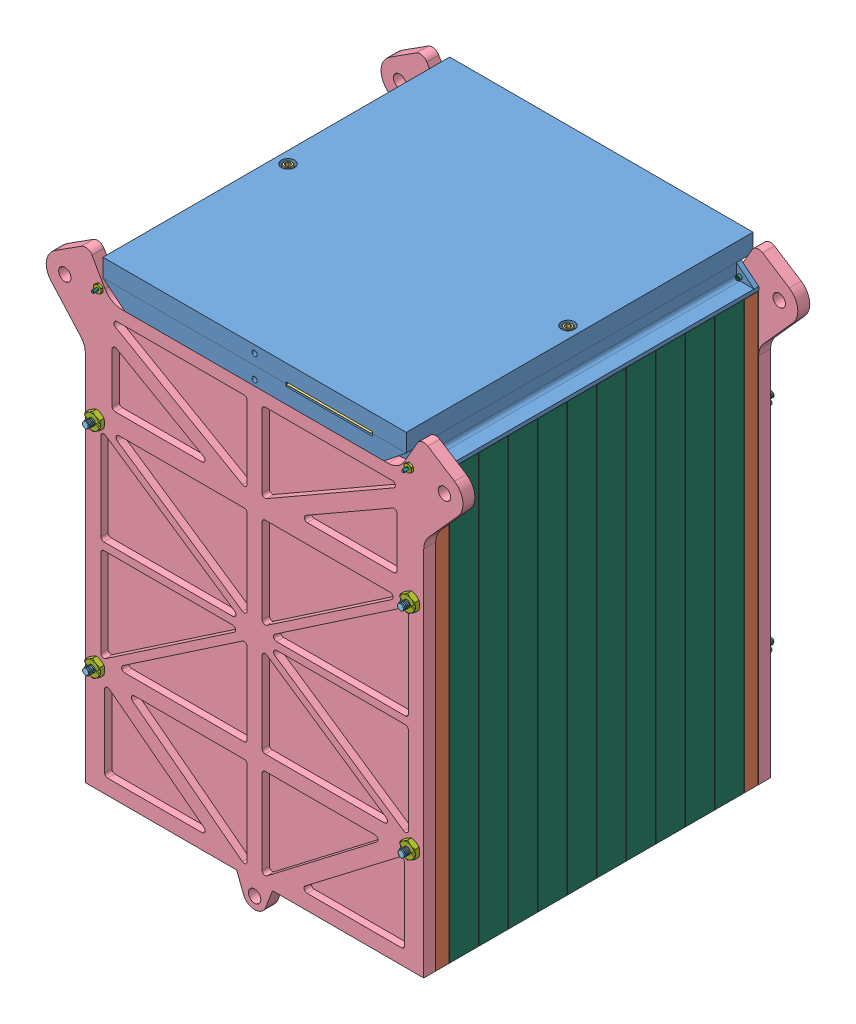
SolidWorks assembly Even Stack, configuration Default. Lengths in mm.
Overall size (221.56 260.06 197.4).
291 component instances, 25 part files, 68 mates.
Components (placement in the parent):
- Tab Cover Even-1: Tab Cover Even [Default] at (178.2277 374.9734 444.4742) x (-1 0 0) z (0 -1 0) size (180.05 184.28 19.05)
- Steel Hex 4-40 Grade 2-1: Steel Hex 4-40 Grade 2 [90480A005] at (103.8227 367.2577 444.4742) size (6.35 2.87 7.33)
- Steel Hex 4-40 Grade 2-2: Steel Hex 4-40 Grade 2 [90480A005] at (252.6327 367.2577 444.4742) size (6.35 2.87 7.33)
- Socket 4-40 0.625in-3: Socket 4-40 0.625in [91251A112] at (103.8227 365.6234 444.4742) x (0.871261 0 -0.49082) z (0 -1 0) size (4.65 4.65 19.13)
- Socket 4-40 0.625in-4: Socket 4-40 0.625in [91251A112] at (252.6327 365.6234 444.4742) x (1 0 0) z (0 -1 0) size (4.65 4.65 19.13)
- Two Cell Module-1: Two Cell Module [Default] at (101.24 129.6114 180.5218) size (179.74 245.1 23.68)
  - Cell Tab Config A-1: Cell Tab Config A [Default<As Machined>] at (76.9877 122.2307 189.17) size (160.6 237.16 14.27)
  - Cell Tab Config B-1: Cell Tab Config B [Default<As Machined>] at (76.9877 122.2307 197.4606) x (-1 0 0) z (0 0 -1) size (160.6 237.16 14.66)
  - Tab Load Spreader-1: Tab Load Spreader [Default] at (116.6877 245.8907 191.0069) x (-1 0 0) z (0 1 0) size (56.96 6.41 2.54)
  - Tab Load Spreader-2: Tab Load Spreader [Default] at (37.2877 245.8907 183.3655) x (-1 0 0) z (0 1 0) size (56.96 6.41 2.54)
  - Tab Load Spreader-3: Tab Load Spreader [Default] at (116.6877 242.8507 191.0069) x (-1 0 0) z (0 1 0) size (56.96 6.41 2.54)
  - Tab Load Spreader-4: Tab Load Spreader [Default] at (37.2877 242.8507 183.3655) x (-1 0 0) z (0 1 0) size (56.96 6.41 2.54)
  - Steel Toplock 6-32 Grade 2-1: Steel Toplock 6-32 Grade 2 [91837A008] at (141.9657 242.8507 191.0069) x (1 0 0) z (0 -1 0) size (7.94 9.17 3.14)
  - Steel 6-32 0.4375in-1: Steel 6-32 0.4375in [91251A178] at (141.9657 237.3182 191.0069) x (1 0 0) z (0 -1 0) size (5.74 5.74 15.07)
  - Steel Toplock 6-32 Grade 2-2: Steel Toplock 6-32 Grade 2 [91837A008] at (91.4097 242.8507 191.0069) x (1 0 0) z (0 -1 0) size (7.94 9.17 3.14)
  - Steel Toplock 6-32 Grade 2-3: Steel Toplock 6-32 Grade 2 [91837A008] at (62.5657 242.8507 183.3655) x (1 0 0) z (0 -1 0) size (7.94 9.17 3.14)
  - Steel Toplock 6-32 Grade 2-4: Steel Toplock 6-32 Grade 2 [91837A008] at (12.0097 242.8507 183.3655) x (1 0 0) z (0 -1 0) size (7.94 9.17 3.14)
  - Steel 6-32 0.4375in-2: Steel 6-32 0.4375in [91251A178] at (91.4097 237.3182 191.0069) x (1 0 0) z (0 -1 0) size (5.74 5.74 15.07)
  - Steel 6-32 0.4375in-3: Steel 6-32 0.4375in [91251A178] at (62.5657 237.3182 183.3655) x (1 0 0) z (0 -1 0) size (5.74 5.74 15.07)
  - Steel 6-32 0.4375in-4: Steel 6-32 0.4375in [91251A178] at (12.0097 237.3182 183.3655) x (1 0 0) z (0 -1 0) size (5.74 5.74 15.07)
  - Cell Board Middle-1: Cell Board Middle [Default] at (76.9877 244.9032 188.87) x (-1 0 0) z (0 0 1) size (20.32 17.15 2.64)
  - Cell Board Middle-2: Cell Board Middle [Default] at (76.9877 244.9032 197.1606) size (20.32 17.15 2.64)
  - Repeating Frame Outer-1: Repeating Frame Outer [Default] at (76.9877 115.9807 198.7766) size (179.3 226.63 1.59)
  - Repeating Frame Outer-2: Repeating Frame Outer [Default] at (76.9877 115.9807 186.2665) size (179.3 226.63 1.59)
  - Repeating Frame Inner-1: Repeating Frame Inner [Default] at (76.9877 116.0307 190.8106) size (179.3 226.73 6.35)
  - Insulation Film Back-1: Insulation Film Back [Default] at (76.9877 122.0246 185.62) x (-1 0 0) z (0 0 -1) size (179.74 227.29 0.36)
  - Insulation Film Full-1: Insulation Film Full [Default] at (76.9876 122.0664 201.0792) x (-1 0 0) z (0 0 -1) size (179.74 227.22 15.52)
  - Cell Load Spreader-1: Cell Load Spreader [Default] at (76.9877 115.9807 192.72) size (154 205.5 1.19)
  - Heat Sink Full-1: Heat Sink Full [Default] at (76.9877 122.0321 201.2316) x (-1 0 0) z (0 0 -1) size (179.74 227.15 15.45)
- Positive End Module-1: Positive End Module [Default] at (225.9097 129.8563 535.5842) x (-1 0 0) z (0 0 -1) size (179.74 245.1 14.97)
  - Cell Tab Config B Positive End-1: Cell Tab Config B Positive End [Default<As Machined>] at (47.682 121.9858 173.2819) size (160.6 236.86 14.97)
  - Repeating Frame Outer-1: Repeating Frame Outer [Default] at (47.682 115.7358 173.5819) size (179.3 226.63 1.59)
  - Repeating Frame Outer-2: Repeating Frame Outer [Default] at (47.682 115.7358 175.1694) size (179.3 226.63 1.59)
  - Repeating Frame Outer-3: Repeating Frame Outer [Default] at (47.682 115.7358 170.3784) size (179.3 226.63 1.59)
  - Cell Board End-1: Cell Board End [Default] at (47.682 240.5308 169.1719) x (-1 0 0) z (0 0 1) size (20.32 25.4 3.91)
  - Insulation Film Half-1: Insulation Film Half [Default] at (47.682 121.8215 169.6633) size (179.74 227.22 7.27)
  - Insulation Film End-1: Insulation Film End [Default] at (47.682 115.7358 176.8319) size (154 205.5 0.07)
  - Heat Sink Half-1: Heat Sink Half [Default] at (47.682 121.7872 169.5109) size (179.74 227.15 7.2)
- Negative End Module Even-2: Negative End Module Even [Default] at (88.6187 141.9749 342.8217) size (179.74 245.1 20.51)
  - Cell Tab Config A Negative End-1: Cell Tab Config A Negative End [Default<As Machined>] at (89.6089 109.8672 183.6722) size (160.6 237.16 19.13)
  - Tab Load Spreader-1: Tab Load Spreader [Default] at (49.9089 233.5272 177.8676) x (1 0 0) z (0 1 0) size (56.96 6.41 2.54)
  - Tab Load Spreader-2: Tab Load Spreader [Default] at (49.9089 233.0272 177.8676) x (1 0 0) z (0 -1 0) size (56.96 6.41 2.54)
  - Steel Toplock 6-32 Grade 2-1: Steel Toplock 6-32 Grade 2 [91837A008] at (24.6309 230.4872 177.8676) x (1 0 0) z (0 -1 0) size (7.94 9.17 3.14)
  - Steel Toplock 6-32 Grade 2-2: Steel Toplock 6-32 Grade 2 [91837A008] at (75.1869 230.4872 177.8676) x (1 0 0) z (0 -1 0) size (7.94 9.17 3.14)
  - Steel 6-32 0.4375in-1: Steel 6-32 0.4375in [91251A178] at (24.6309 224.9547 177.8676) x (1 0 0) z (0 -1 0) size (5.74 5.74 15.07)
  - Steel 6-32 0.4375in-2: Steel 6-32 0.4375in [91251A178] at (75.1869 224.9547 177.8676) x (1 0 0) z (0 -1 0) size (5.74 5.74 15.07)
  - Repeating Frame Outer-1: Repeating Frame Outer [Default] at (89.6089 103.6172 185.5597) size (179.3 226.63 1.59)
  - Repeating Frame Outer-2: Repeating Frame Outer [Default] at (89.6089 103.6172 183.9722) size (179.3 226.63 1.59)
  - Repeating Frame Outer-3: Repeating Frame Outer [Default] at (89.6089 103.6172 180.7687) size (179.3 226.63 1.59)
  - Insulation Film Back-1: Insulation Film Back [Default] at (89.609 109.661 180.1222) x (-1 0 0) z (0 0 -1) size (179.74 227.29 0.36)
  - Insulation Film Half-1: Insulation Film Half [Default] at (89.6089 109.703 187.2908) x (-1 0 0) z (0 0 -1) size (179.74 227.22 7.27)
  - Cell Board End-1: Cell Board End [Default] at (89.6089 228.4122 179.5622) x (-1 0 0) z (0 0 1) size (20.32 25.4 3.91)
  - Heat Sink Half-1: Heat Sink Half [Default] at (89.6089 109.6686 187.4432) x (-1 0 0) z (0 0 -1) size (179.74 227.15 7.2)
- Two Cell Module-2: Two Cell Module [Default] at (101.24 129.6114 196.202) size (179.74 245.1 23.68)
  - Cell Tab Config A-1: Cell Tab Config A [Default<As Machined>] at (76.9877 122.2307 189.17) size (160.6 237.16 14.27)
  - Cell Tab Config B-1: Cell Tab Config B [Default<As Machined>] at (76.9877 122.2307 197.4606) x (-1 0 0) z (0 0 -1) size (160.6 237.16 14.66)
  - Tab Load Spreader-1: Tab Load Spreader [Default] at (116.6877 245.8907 191.0069) x (-1 0 0) z (0 1 0) size (56.96 6.41 2.54)
  - Tab Load Spreader-2: Tab Load Spreader [Default] at (37.2877 245.8907 183.3655) x (-1 0 0) z (0 1 0) size (56.96 6.41 2.54)
  - Tab Load Spreader-3: Tab Load Spreader [Default] at (116.6877 242.8507 191.0069) x (-1 0 0) z (0 1 0) size (56.96 6.41 2.54)
  - Tab Load Spreader-4: Tab Load Spreader [Default] at (37.2877 242.8507 183.3655) x (-1 0 0) z (0 1 0) size (56.96 6.41 2.54)
  - Steel Toplock 6-32 Grade 2-1: Steel Toplock 6-32 Grade 2 [91837A008] at (141.9657 242.8507 191.0069) x (1 0 0) z (0 -1 0) size (7.94 9.17 3.14)
  - Steel 6-32 0.4375in-1: Steel 6-32 0.4375in [91251A178] at (141.9657 237.3182 191.0069) x (1 0 0) z (0 -1 0) size (5.74 5.74 15.07)
  - Steel Toplock 6-32 Grade 2-2: Steel Toplock 6-32 Grade 2 [91837A008] at (91.4097 242.8507 191.0069) x (1 0 0) z (0 -1 0) size (7.94 9.17 3.14)
  - Steel Toplock 6-32 Grade 2-3: Steel Toplock 6-32 Grade 2 [91837A008] at (62.5657 242.8507 183.3655) x (1 0 0) z (0 -1 0) size (7.94 9.17 3.14)
  - Steel Toplock 6-32 Grade 2-4: Steel Toplock 6-32 Grade 2 [91837A008] at (12.0097 242.8507 183.3655) x (1 0 0) z (0 -1 0) size (7.94 9.17 3.14)
  - Steel 6-32 0.4375in-2: Steel 6-32 0.4375in [91251A178] at (91.4097 237.3182 191.0069) x (1 0 0) z (0 -1 0) size (5.74 5.74 15.07)
  - Steel 6-32 0.4375in-3: Steel 6-32 0.4375in [91251A178] at (62.5657 237.3182 183.3655) x (1 0 0) z (0 -1 0) size (5.74 5.74 15.07)
  - Steel 6-32 0.4375in-4: Steel 6-32 0.4375in [91251A178] at (12.0097 237.3182 183.3655) x (1 0 0) z (0 -1 0) size (5.74 5.74 15.07)
  - Cell Board Middle-1: Cell Board Middle [Default] at (76.9877 244.9032 188.87) x (-1 0 0) z (0 0 1) size (20.32 17.15 2.64)
  - Cell Board Middle-2: Cell Board Middle [Default] at (76.9877 244.9032 197.1606) size (20.32 17.15 2.64)
  - Repeating Frame Outer-1: Repeating Frame Outer [Default] at (76.9877 115.9807 198.7766) size (179.3 226.63 1.59)
  - Repeating Frame Outer-2: Repeating Frame Outer [Default] at (76.9877 115.9807 186.2665) size (179.3 226.63 1.59)
  - Repeating Frame Inner-1: Repeating Frame Inner [Default] at (76.9877 116.0307 190.8106) size (179.3 226.73 6.35)
  - Insulation Film Back-1: Insulation Film Back [Default] at (76.9877 122.0246 185.62) x (-1 0 0) z (0 0 -1) size (179.74 227.29 0.36)
  - Insulation Film Full-1: Insulation Film Full [Default] at (76.9876 122.0664 201.0792) x (-1 0 0) z (0 0 -1) size (179.74 227.22 15.52)
  - Cell Load Spreader-1: Cell Load Spreader [Default] at (76.9877 115.9807 192.72) size (154 205.5 1.19)
  - Heat Sink Full-1: Heat Sink Full [Default] at (76.9877 122.0321 201.2316) x (-1 0 0) z (0 0 -1) size (179.74 227.15 15.45)
- Two Cell Module-3: Two Cell Module [Default] at (101.24 129.6114 211.8822) size (179.74 245.1 23.68)
  - Cell Tab Config A-1: Cell Tab Config A [Default<As Machined>] at (76.9877 122.2307 189.17) size (160.6 237.16 14.27)
  - Cell Tab Config B-1: Cell Tab Config B [Default<As Machined>] at (76.9877 122.2307 197.4606) x (-1 0 0) z (0 0 -1) size (160.6 237.16 14.66)
  - Tab Load Spreader-1: Tab Load Spreader [Default] at (116.6877 245.8907 191.0069) x (-1 0 0) z (0 1 0) size (56.96 6.41 2.54)
  - Tab Load Spreader-2: Tab Load Spreader [Default] at (37.2877 245.8907 183.3655) x (-1 0 0) z (0 1 0) size (56.96 6.41 2.54)
  - Tab Load Spreader-3: Tab Load Spreader [Default] at (116.6877 242.8507 191.0069) x (-1 0 0) z (0 1 0) size (56.96 6.41 2.54)
  - Tab Load Spreader-4: Tab Load Spreader [Default] at (37.2877 242.8507 183.3655) x (-1 0 0) z (0 1 0) size (56.96 6.41 2.54)
  - Steel Toplock 6-32 Grade 2-1: Steel Toplock 6-32 Grade 2 [91837A008] at (141.9657 242.8507 191.0069) x (1 0 0) z (0 -1 0) size (7.94 9.17 3.14)
  - Steel 6-32 0.4375in-1: Steel 6-32 0.4375in [91251A178] at (141.9657 237.3182 191.0069) x (1 0 0) z (0 -1 0) size (5.74 5.74 15.07)
  - Steel Toplock 6-32 Grade 2-2: Steel Toplock 6-32 Grade 2 [91837A008] at (91.4097 242.8507 191.0069) x (1 0 0) z (0 -1 0) size (7.94 9.17 3.14)
  - Steel Toplock 6-32 Grade 2-3: Steel Toplock 6-32 Grade 2 [91837A008] at (62.5657 242.8507 183.3655) x (1 0 0) z (0 -1 0) size (7.94 9.17 3.14)
  - Steel Toplock 6-32 Grade 2-4: Steel Toplock 6-32 Grade 2 [91837A008] at (12.0097 242.8507 183.3655) x (1 0 0) z (0 -1 0) size (7.94 9.17 3.14)
  - Steel 6-32 0.4375in-2: Steel 6-32 0.4375in [91251A178] at (91.4097 237.3182 191.0069) x (1 0 0) z (0 -1 0) size (5.74 5.74 15.07)
  - Steel 6-32 0.4375in-3: Steel 6-32 0.4375in [91251A178] at (62.5657 237.3182 183.3655) x (1 0 0) z (0 -1 0) size (5.74 5.74 15.07)
  - Steel 6-32 0.4375in-4: Steel 6-32 0.4375in [91251A178] at (12.0097 237.3182 183.3655) x (1 0 0) z (0 -1 0) size (5.74 5.74 15.07)
  - Cell Board Middle-1: Cell Board Middle [Default] at (76.9877 244.9032 188.87) x (-1 0 0) z (0 0 1) size (20.32 17.15 2.64)
  - Cell Board Middle-2: Cell Board Middle [Default] at (76.9877 244.9032 197.1606) size (20.32 17.15 2.64)
  - Repeating Frame Outer-1: Repeating Frame Outer [Default] at (76.9877 115.9807 198.7766) size (179.3 226.63 1.59)
  - Repeating Frame Outer-2: Repeating Frame Outer [Default] at (76.9877 115.9807 186.2665) size (179.3 226.63 1.59)
  - Repeating Frame Inner-1: Repeating Frame Inner [Default] at (76.9877 116.0307 190.8106) size (179.3 226.73 6.35)
  - Insulation Film Back-1: Insulation Film Back [Default] at (76.9877 122.0246 185.62) x (-1 0 0) z (0 0 -1) size (179.74 227.29 0.36)
  - Insulation Film Full-1: Insulation Film Full [Default] at (76.9876 122.0664 201.0792) x (-1 0 0) z (0 0 -1) size (179.74 227.22 15.52)
  - Cell Load Spreader-1: Cell Load Spreader [Default] at (76.9877 115.9807 192.72) size (154 205.5 1.19)
  - Heat Sink Full-1: Heat Sink Full [Default] at (76.9877 122.0321 201.2316) x (-1 0 0) z (0 0 -1) size (179.74 227.15 15.45)
- Two Cell Module-4: Two Cell Module [Default] at (101.24 129.6114 227.5624) size (179.74 245.1 23.68)
  - Cell Tab Config A-1: Cell Tab Config A [Default<As Machined>] at (76.9877 122.2307 189.17) size (160.6 237.16 14.27)
  - Cell Tab Config B-1: Cell Tab Config B [Default<As Machined>] at (76.9877 122.2307 197.4606) x (-1 0 0) z (0 0 -1) size (160.6 237.16 14.66)
  - Tab Load Spreader-1: Tab Load Spreader [Default] at (116.6877 245.8907 191.0069) x (-1 0 0) z (0 1 0) size (56.96 6.41 2.54)
  - Tab Load Spreader-2: Tab Load Spreader [Default] at (37.2877 245.8907 183.3655) x (-1 0 0) z (0 1 0) size (56.96 6.41 2.54)
  - Tab Load Spreader-3: Tab Load Spreader [Default] at (116.6877 242.8507 191.0069) x (-1 0 0) z (0 1 0) size (56.96 6.41 2.54)
  - Tab Load Spreader-4: Tab Load Spreader [Default] at (37.2877 242.8507 183.3655) x (-1 0 0) z (0 1 0) size (56.96 6.41 2.54)
  - Steel Toplock 6-32 Grade 2-1: Steel Toplock 6-32 Grade 2 [91837A008] at (141.9657 242.8507 191.0069) x (1 0 0) z (0 -1 0) size (7.94 9.17 3.14)
  - Steel 6-32 0.4375in-1: Steel 6-32 0.4375in [91251A178] at (141.9657 237.3182 191.0069) x (1 0 0) z (0 -1 0) size (5.74 5.74 15.07)
  - Steel Toplock 6-32 Grade 2-2: Steel Toplock 6-32 Grade 2 [91837A008] at (91.4097 242.8507 191.0069) x (1 0 0) z (0 -1 0) size (7.94 9.17 3.14)
  - Steel Toplock 6-32 Grade 2-3: Steel Toplock 6-32 Grade 2 [91837A008] at (62.5657 242.8507 183.3655) x (1 0 0) z (0 -1 0) size (7.94 9.17 3.14)
  - Steel Toplock 6-32 Grade 2-4: Steel Toplock 6-32 Grade 2 [91837A008] at (12.0097 242.8507 183.3655) x (1 0 0) z (0 -1 0) size (7.94 9.17 3.14)
  - Steel 6-32 0.4375in-2: Steel 6-32 0.4375in [91251A178] at (91.4097 237.3182 191.0069) x (1 0 0) z (0 -1 0) size (5.74 5.74 15.07)
  - Steel 6-32 0.4375in-3: Steel 6-32 0.4375in [91251A178] at (62.5657 237.3182 183.3655) x (1 0 0) z (0 -1 0) size (5.74 5.74 15.07)
  - Steel 6-32 0.4375in-4: Steel 6-32 0.4375in [91251A178] at (12.0097 237.3182 183.3655) x (1 0 0) z (0 -1 0) size (5.74 5.74 15.07)
  - Cell Board Middle-1: Cell Board Middle [Default] at (76.9877 244.9032 188.87) x (-1 0 0) z (0 0 1) size (20.32 17.15 2.64)
  - Cell Board Middle-2: Cell Board Middle [Default] at (76.9877 244.9032 197.1606) size (20.32 17.15 2.64)
  - Repeating Frame Outer-1: Repeating Frame Outer [Default] at (76.9877 115.9807 198.7766) size (179.3 226.63 1.59)
  - Repeating Frame Outer-2: Repeating Frame Outer [Default] at (76.9877 115.9807 186.2665) size (179.3 226.63 1.59)
  - Repeating Frame Inner-1: Repeating Frame Inner [Default] at (76.9877 116.0307 190.8106) size (179.3 226.73 6.35)
  - Insulation Film Back-1: Insulation Film Back [Default] at (76.9877 122.0246 185.62) x (-1 0 0) z (0 0 -1) size (179.74 227.29 0.36)
  - Insulation Film Full-1: Insulation Film Full [Default] at (76.9876 122.0664 201.0792) x (-1 0 0) z (0 0 -1) size (179.74 227.22 15.52)
  - Cell Load Spreader-1: Cell Load Spreader [Default] at (76.9877 115.9807 192.72) size (154 205.5 1.19)
  - Heat Sink Full-1: Heat Sink Full [Default] at (76.9877 122.0321 201.2316) x (-1 0 0) z (0 0 -1) size (179.74 227.15 15.45)
- Two Cell Module-5: Two Cell Module [Default] at (101.24 129.6114 243.2426) size (179.74 245.1 23.68)
  - Cell Tab Config A-1: Cell Tab Config A [Default<As Machined>] at (76.9877 122.2307 189.17) size (160.6 237.16 14.27)
  - Cell Tab Config B-1: Cell Tab Config B [Default<As Machined>] at (76.9877 122.2307 197.4606) x (-1 0 0) z (0 0 -1) size (160.6 237.16 14.66)
  - Tab Load Spreader-1: Tab Load Spreader [Default] at (116.6877 245.8907 191.0069) x (-1 0 0) z (0 1 0) size (56.96 6.41 2.54)
  - Tab Load Spreader-2: Tab Load Spreader [Default] at (37.2877 245.8907 183.3655) x (-1 0 0) z (0 1 0) size (56.96 6.41 2.54)
  - Tab Load Spreader-3: Tab Load Spreader [Default] at (116.6877 242.8507 191.0069) x (-1 0 0) z (0 1 0) size (56.96 6.41 2.54)
  - Tab Load Spreader-4: Tab Load Spreader [Default] at (37.2877 242.8507 183.3655) x (-1 0 0) z (0 1 0) size (56.96 6.41 2.54)
  - Steel Toplock 6-32 Grade 2-1: Steel Toplock 6-32 Grade 2 [91837A008] at (141.9657 242.8507 191.0069) x (1 0 0) z (0 -1 0) size (7.94 9.17 3.14)
  - Steel 6-32 0.4375in-1: Steel 6-32 0.4375in [91251A178] at (141.9657 237.3182 191.0069) x (1 0 0) z (0 -1 0) size (5.74 5.74 15.07)
  - Steel Toplock 6-32 Grade 2-2: Steel Toplock 6-32 Grade 2 [91837A008] at (91.4097 242.8507 191.0069) x (1 0 0) z (0 -1 0) size (7.94 9.17 3.14)
  - Steel Toplock 6-32 Grade 2-3: Steel Toplock 6-32 Grade 2 [91837A008] at (62.5657 242.8507 183.3655) x (1 0 0) z (0 -1 0) size (7.94 9.17 3.14)
  - Steel Toplock 6-32 Grade 2-4: Steel Toplock 6-32 Grade 2 [91837A008] at (12.0097 242.8507 183.3655) x (1 0 0) z (0 -1 0) size (7.94 9.17 3.14)
  - Steel 6-32 0.4375in-2: Steel 6-32 0.4375in [91251A178] at (91.4097 237.3182 191.0069) x (1 0 0) z (0 -1 0) size (5.74 5.74 15.07)
  - Steel 6-32 0.4375in-3: Steel 6-32 0.4375in [91251A178] at (62.5657 237.3182 183.3655) x (1 0 0) z (0 -1 0) size (5.74 5.74 15.07)
  - Steel 6-32 0.4375in-4: Steel 6-32 0.4375in [91251A178] at (12.0097 237.3182 183.3655) x (1 0 0) z (0 -1 0) size (5.74 5.74 15.07)
  - Cell Board Middle-1: Cell Board Middle [Default] at (76.9877 244.9032 188.87) x (-1 0 0) z (0 0 1) size (20.32 17.15 2.64)
  - Cell Board Middle-2: Cell Board Middle [Default] at (76.9877 244.9032 197.1606) size (20.32 17.15 2.64)
  - Repeating Frame Outer-1: Repeating Frame Outer [Default] at (76.9877 115.9807 198.7766) size (179.3 226.63 1.59)
  - Repeating Frame Outer-2: Repeating Frame Outer [Default] at (76.9877 115.9807 186.2665) size (179.3 226.63 1.59)
  - Repeating Frame Inner-1: Repeating Frame Inner [Default] at (76.9877 116.0307 190.8106) size (179.3 226.73 6.35)
  - Insulation Film Back-1: Insulation Film Back [Default] at (76.9877 122.0246 185.62) x (-1 0 0) z (0 0 -1) size (179.74 227.29 0.36)
  - Insulation Film Full-1: Insulation Film Full [Default] at (76.9876 122.0664 201.0792) x (-1 0 0) z (0 0 -1) size (179.74 227.22 15.52)
  - Cell Load Spreader-1: Cell Load Spreader [Default] at (76.9877 115.9807 192.72) size (154 205.5 1.19)
  - Heat Sink Full-1: Heat Sink Full [Default] at (76.9877 122.0321 201.2316) x (-1 0 0) z (0 0 -1) size (179.74 227.15 15.45)
- Two Cell Module-6: Two Cell Module [Default] at (101.24 129.6114 258.9228) size (179.74 245.1 23.68)
  - Cell Tab Config A-1: Cell Tab Config A [Default<As Machined>] at (76.9877 122.2307 189.17) size (160.6 237.16 14.27)
  - Cell Tab Config B-1: Cell Tab Config B [Default<As Machined>] at (76.9877 122.2307 197.4606) x (-1 0 0) z (0 0 -1) size (160.6 237.16 14.66)
  - Tab Load Spreader-1: Tab Load Spreader [Default] at (116.6877 245.8907 191.0069) x (-1 0 0) z (0 1 0) size (56.96 6.41 2.54)
  - Tab Load Spreader-2: Tab Load Spreader [Default] at (37.2877 245.8907 183.3655) x (-1 0 0) z (0 1 0) size (56.96 6.41 2.54)
  - Tab Load Spreader-3: Tab Load Spreader [Default] at (116.6877 242.8507 191.0069) x (-1 0 0) z (0 1 0) size (56.96 6.41 2.54)
  - Tab Load Spreader-4: Tab Load Spreader [Default] at (37.2877 242.8507 183.3655) x (-1 0 0) z (0 1 0) size (56.96 6.41 2.54)
  - Steel Toplock 6-32 Grade 2-1: Steel Toplock 6-32 Grade 2 [91837A008] at (141.9657 242.8507 191.0069) x (1 0 0) z (0 -1 0) size (7.94 9.17 3.14)
  - Steel 6-32 0.4375in-1: Steel 6-32 0.4375in [91251A178] at (141.9657 237.3182 191.0069) x (1 0 0) z (0 -1 0) size (5.74 5.74 15.07)
  - Steel Toplock 6-32 Grade 2-2: Steel Toplock 6-32 Grade 2 [91837A008] at (91.4097 242.8507 191.0069) x (1 0 0) z (0 -1 0) size (7.94 9.17 3.14)
  - Steel Toplock 6-32 Grade 2-3: Steel Toplock 6-32 Grade 2 [91837A008] at (62.5657 242.8507 183.3655) x (1 0 0) z (0 -1 0) size (7.94 9.17 3.14)
  - Steel Toplock 6-32 Grade 2-4: Steel Toplock 6-32 Grade 2 [91837A008] at (12.0097 242.8507 183.3655) x (1 0 0) z (0 -1 0) size (7.94 9.17 3.14)
  - Steel 6-32 0.4375in-2: Steel 6-32 0.4375in [91251A178] at (91.4097 237.3182 191.0069) x (1 0 0) z (0 -1 0) size (5.74 5.74 15.07)
  - Steel 6-32 0.4375in-3: Steel 6-32 0.4375in [91251A178] at (62.5657 237.3182 183.3655) x (1 0 0) z (0 -1 0) size (5.74 5.74 15.07)
  - Steel 6-32 0.4375in-4: Steel 6-32 0.4375in [91251A178] at (12.0097 237.3182 183.3655) x (1 0 0) z (0 -1 0) size (5.74 5.74 15.07)
  - Cell Board Middle-1: Cell Board Middle [Default] at (76.9877 244.9032 188.87) x (-1 0 0) z (0 0 1) size (20.32 17.15 2.64)
  - Cell Board Middle-2: Cell Board Middle [Default] at (76.9877 244.9032 197.1606) size (20.32 17.15 2.64)
  - Repeating Frame Outer-1: Repeating Frame Outer [Default] at (76.9877 115.9807 198.7766) size (179.3 226.63 1.59)
  - Repeating Frame Outer-2: Repeating Frame Outer [Default] at (76.9877 115.9807 186.2665) size (179.3 226.63 1.59)
  - Repeating Frame Inner-1: Repeating Frame Inner [Default] at (76.9877 116.0307 190.8106) size (179.3 226.73 6.35)
  - Insulation Film Back-1: Insulation Film Back [Default] at (76.9877 122.0246 185.62) x (-1 0 0) z (0 0 -1) size (179.74 227.29 0.36)
  - Insulation Film Full-1: Insulation Film Full [Default] at (76.9876 122.0664 201.0792) x (-1 0 0) z (0 0 -1) size (179.74 227.22 15.52)
  - Cell Load Spreader-1: Cell Load Spreader [Default] at (76.9877 115.9807 192.72) size (154 205.5 1.19)
  - Heat Sink Full-1: Heat Sink Full [Default] at (76.9877 122.0321 201.2316) x (-1 0 0) z (0 0 -1) size (179.74 227.15 15.45)
- Two Cell Module-7: Two Cell Module [Default] at (101.24 129.6114 274.603) size (179.74 245.1 23.68)
  - Cell Tab Config A-1: Cell Tab Config A [Default<As Machined>] at (76.9877 122.2307 189.17) size (160.6 237.16 14.27)
  - Cell Tab Config B-1: Cell Tab Config B [Default<As Machined>] at (76.9877 122.2307 197.4606) x (-1 0 0) z (0 0 -1) size (160.6 237.16 14.66)
  - Tab Load Spreader-1: Tab Load Spreader [Default] at (116.6877 245.8907 191.0069) x (-1 0 0) z (0 1 0) size (56.96 6.41 2.54)
  - Tab Load Spreader-2: Tab Load Spreader [Default] at (37.2877 245.8907 183.3655) x (-1 0 0) z (0 1 0) size (56.96 6.41 2.54)
  - Tab Load Spreader-3: Tab Load Spreader [Default] at (116.6877 242.8507 191.0069) x (-1 0 0) z (0 1 0) size (56.96 6.41 2.54)
  - Tab Load Spreader-4: Tab Load Spreader [Default] at (37.2877 242.8507 183.3655) x (-1 0 0) z (0 1 0) size (56.96 6.41 2.54)
  - Steel Toplock 6-32 Grade 2-1: Steel Toplock 6-32 Grade 2 [91837A008] at (141.9657 242.8507 191.0069) x (1 0 0) z (0 -1 0) size (7.94 9.17 3.14)
  - Steel 6-32 0.4375in-1: Steel 6-32 0.4375in [91251A178] at (141.9657 237.3182 191.0069) x (1 0 0) z (0 -1 0) size (5.74 5.74 15.07)
  - Steel Toplock 6-32 Grade 2-2: Steel Toplock 6-32 Grade 2 [91837A008] at (91.4097 242.8507 191.0069) x (1 0 0) z (0 -1 0) size (7.94 9.17 3.14)
  - Steel Toplock 6-32 Grade 2-3: Steel Toplock 6-32 Grade 2 [91837A008] at (62.5657 242.8507 183.3655) x (1 0 0) z (0 -1 0) size (7.94 9.17 3.14)
  - Steel Toplock 6-32 Grade 2-4: Steel Toplock 6-32 Grade 2 [91837A008] at (12.0097 242.8507 183.3655) x (1 0 0) z (0 -1 0) size (7.94 9.17 3.14)
  - Steel 6-32 0.4375in-2: Steel 6-32 0.4375in [91251A178] at (91.4097 237.3182 191.0069) x (1 0 0) z (0 -1 0) size (5.74 5.74 15.07)
  - Steel 6-32 0.4375in-3: Steel 6-32 0.4375in [91251A178] at (62.5657 237.3182 183.3655) x (1 0 0) z (0 -1 0) size (5.74 5.74 15.07)
  - Steel 6-32 0.4375in-4: Steel 6-32 0.4375in [91251A178] at (12.0097 237.3182 183.3655) x (1 0 0) z (0 -1 0) size (5.74 5.74 15.07)
  - Cell Board Middle-1: Cell Board Middle [Default] at (76.9877 244.9032 188.87) x (-1 0 0) z (0 0 1) size (20.32 17.15 2.64)
  - Cell Board Middle-2: Cell Board Middle [Default] at (76.9877 244.9032 197.1606) size (20.32 17.15 2.64)
  - Repeating Frame Outer-1: Repeating Frame Outer [Default] at (76.9877 115.9807 198.7766) size (179.3 226.63 1.59)
  - Repeating Frame Outer-2: Repeating Frame Outer [Default] at (76.9877 115.9807 186.2665) size (179.3 226.63 1.59)
  - Repeating Frame Inner-1: Repeating Frame Inner [Default] at (76.9877 116.0307 190.8106) size (179.3 226.73 6.35)
  - Insulation Film Back-1: Insulation Film Back [Default] at (76.9877 122.0246 185.62) x (-1 0 0) z (0 0 -1) size (179.74 227.29 0.36)
  - Insulation Film Full-1: Insulation Film Full [Default] at (76.9876 122.0664 201.0792) x (-1 0 0) z (0 0 -1) size (179.74 227.22 15.52)
  - Cell Load Spreader-1: Cell Load Spreader [Default] at (76.9877 115.9807 192.72) size (154 205.5 1.19)
  - Heat Sink Full-1: Heat Sink Full [Default] at (76.9877 122.0321 201.2316) x (-1 0 0) z (0 0 -1) size (179.74 227.15 15.45)
- Two Cell Module-8: Two Cell Module [Default] at (101.24 129.6114 290.2832) size (179.74 245.1 23.68)
  - Cell Tab Config A-1: Cell Tab Config A [Default<As Machined>] at (76.9877 122.2307 189.17) size (160.6 237.16 14.27)
  - Cell Tab Config B-1: Cell Tab Config B [Default<As Machined>] at (76.9877 122.2307 197.4606) x (-1 0 0) z (0 0 -1) size (160.6 237.16 14.66)
  - Tab Load Spreader-1: Tab Load Spreader [Default] at (116.6877 245.8907 191.0069) x (-1 0 0) z (0 1 0) size (56.96 6.41 2.54)
  - Tab Load Spreader-2: Tab Load Spreader [Default] at (37.2877 245.8907 183.3655) x (-1 0 0) z (0 1 0) size (56.96 6.41 2.54)
  - Tab Load Spreader-3: Tab Load Spreader [Default] at (116.6877 242.8507 191.0069) x (-1 0 0) z (0 1 0) size (56.96 6.41 2.54)
  - Tab Load Spreader-4: Tab Load Spreader [Default] at (37.2877 242.8507 183.3655) x (-1 0 0) z (0 1 0) size (56.96 6.41 2.54)
  - Steel Toplock 6-32 Grade 2-1: Steel Toplock 6-32 Grade 2 [91837A008] at (141.9657 242.8507 191.0069) x (1 0 0) z (0 -1 0) size (7.94 9.17 3.14)
  - Steel 6-32 0.4375in-1: Steel 6-32 0.4375in [91251A178] at (141.9657 237.3182 191.0069) x (1 0 0) z (0 -1 0) size (5.74 5.74 15.07)
  - Steel Toplock 6-32 Grade 2-2: Steel Toplock 6-32 Grade 2 [91837A008] at (91.4097 242.8507 191.0069) x (1 0 0) z (0 -1 0) size (7.94 9.17 3.14)
  - Steel Toplock 6-32 Grade 2-3: Steel Toplock 6-32 Grade 2 [91837A008] at (62.5657 242.8507 183.3655) x (1 0 0) z (0 -1 0) size (7.94 9.17 3.14)
  - Steel Toplock 6-32 Grade 2-4: Steel Toplock 6-32 Grade 2 [91837A008] at (12.0097 242.8507 183.3655) x (1 0 0) z (0 -1 0) size (7.94 9.17 3.14)
  - Steel 6-32 0.4375in-2: Steel 6-32 0.4375in [91251A178] at (91.4097 237.3182 191.0069) x (1 0 0) z (0 -1 0) size (5.74 5.74 15.07)
  - Steel 6-32 0.4375in-3: Steel 6-32 0.4375in [91251A178] at (62.5657 237.3182 183.3655) x (1 0 0) z (0 -1 0) size (5.74 5.74 15.07)
  - Steel 6-32 0.4375in-4: Steel 6-32 0.4375in [91251A178] at (12.0097 237.3182 183.3655) x (1 0 0) z (0 -1 0) size (5.74 5.74 15.07)
  - Cell Board Middle-1: Cell Board Middle [Default] at (76.9877 244.9032 188.87) x (-1 0 0) z (0 0 1) size (20.32 17.15 2.64)
  - Cell Board Middle-2: Cell Board Middle [Default] at (76.9877 244.9032 197.1606) size (20.32 17.15 2.64)
  - Repeating Frame Outer-1: Repeating Frame Outer [Default] at (76.9877 115.9807 198.7766) size (179.3 226.63 1.59)
  - Repeating Frame Outer-2: Repeating Frame Outer [Default] at (76.9877 115.9807 186.2665) size (179.3 226.63 1.59)
  - Repeating Frame Inner-1: Repeating Frame Inner [Default] at (76.9877 116.0307 190.8106) size (179.3 226.73 6.35)
  - Insulation Film Back-1: Insulation Film Back [Default] at (76.9877 122.0246 185.62) x (-1 0 0) z (0 0 -1) size (179.74 227.29 0.36)
  - Insulation Film Full-1: Insulation Film Full [Default] at (76.9876 122.0664 201.0792) x (-1 0 0) z (0 0 -1) size (179.74 227.22 15.52)
  - Cell Load Spreader-1: Cell Load Spreader [Default] at (76.9877 115.9807 192.72) size (154 205.5 1.19)
  - Heat Sink Full-1: Heat Sink Full [Default] at (76.9877 122.0321 201.2316) x (-1 0 0) z (0 0 -1) size (179.74 227.15 15.45)
- Two Cell Module-9: Two Cell Module [Default] at (101.24 129.6114 305.9634) size (179.74 245.1 23.68)
  - Cell Tab Config A-1: Cell Tab Config A [Default<As Machined>] at (76.9877 122.2307 189.17) size (160.6 237.16 14.27)
  - Cell Tab Config B-1: Cell Tab Config B [Default<As Machined>] at (76.9877 122.2307 197.4606) x (-1 0 0) z (0 0 -1) size (160.6 237.16 14.66)
  - Tab Load Spreader-1: Tab Load Spreader [Default] at (116.6877 245.8907 191.0069) x (-1 0 0) z (0 1 0) size (56.96 6.41 2.54)
  - Tab Load Spreader-2: Tab Load Spreader [Default] at (37.2877 245.8907 183.3655) x (-1 0 0) z (0 1 0) size (56.96 6.41 2.54)
  - Tab Load Spreader-3: Tab Load Spreader [Default] at (116.6877 242.8507 191.0069) x (-1 0 0) z (0 1 0) size (56.96 6.41 2.54)
  - Tab Load Spreader-4: Tab Load Spreader [Default] at (37.2877 242.8507 183.3655) x (-1 0 0) z (0 1 0) size (56.96 6.41 2.54)
  - Steel Toplock 6-32 Grade 2-1: Steel Toplock 6-32 Grade 2 [91837A008] at (141.9657 242.8507 191.0069) x (1 0 0) z (0 -1 0) size (7.94 9.17 3.14)
  - Steel 6-32 0.4375in-1: Steel 6-32 0.4375in [91251A178] at (141.9657 237.3182 191.0069) x (1 0 0) z (0 -1 0) size (5.74 5.74 15.07)
  - Steel Toplock 6-32 Grade 2-2: Steel Toplock 6-32 Grade 2 [91837A008] at (91.4097 242.8507 191.0069) x (1 0 0) z (0 -1 0) size (7.94 9.17 3.14)
  - Steel Toplock 6-32 Grade 2-3: Steel Toplock 6-32 Grade 2 [91837A008] at (62.5657 242.8507 183.3655) x (1 0 0) z (0 -1 0) size (7.94 9.17 3.14)
  - Steel Toplock 6-32 Grade 2-4: Steel Toplock 6-32 Grade 2 [91837A008] at (12.0097 242.8507 183.3655) x (1 0 0) z (0 -1 0) size (7.94 9.17 3.14)
  - Steel 6-32 0.4375in-2: Steel 6-32 0.4375in [91251A178] at (91.4097 237.3182 191.0069) x (1 0 0) z (0 -1 0) size (5.74 5.74 15.07)
  - Steel 6-32 0.4375in-3: Steel 6-32 0.4375in [91251A178] at (62.5657 237.3182 183.3655) x (1 0 0) z (0 -1 0) size (5.74 5.74 15.07)
  - Steel 6-32 0.4375in-4: Steel 6-32 0.4375in [91251A178] at (12.0097 237.3182 183.3655) x (1 0 0) z (0 -1 0) size (5.74 5.74 15.07)
  - Cell Board Middle-1: Cell Board Middle [Default] at (76.9877 244.9032 188.87) x (-1 0 0) z (0 0 1) size (20.32 17.15 2.64)
  - Cell Board Middle-2: Cell Board Middle [Default] at (76.9877 244.9032 197.1606) size (20.32 17.15 2.64)
  - Repeating Frame Outer-1: Repeating Frame Outer [Default] at (76.9877 115.9807 198.7766) size (179.3 226.63 1.59)
  - Repeating Frame Outer-2: Repeating Frame Outer [Default] at (76.9877 115.9807 186.2665) size (179.3 226.63 1.59)
  - Repeating Frame Inner-1: Repeating Frame Inner [Default] at (76.9877 116.0307 190.8106) size (179.3 226.73 6.35)
  - Insulation Film Back-1: Insulation Film Back [Default] at (76.9877 122.0246 185.62) x (-1 0 0) z (0 0 -1) size (179.74 227.29 0.36)
  - Insulation Film Full-1: Insulation Film Full [Default] at (76.9876 122.0664 201.0792) x (-1 0 0) z (0 0 -1) size (179.74 227.22 15.52)
  - Cell Load Spreader-1: Cell Load Spreader [Default] at (76.9877 115.9807 192.72) size (154 205.5 1.19)
  - Heat Sink Full-1: Heat Sink Full [Default] at (76.9877 122.0321 201.2316) x (-1 0 0) z (0 0 -1) size (179.74 227.15 15.45)
- Two Cell Module-10: Two Cell Module [Default] at (101.24 129.6114 321.6436) size (179.74 245.1 23.68)
  - Cell Tab Config A-1: Cell Tab Config A [Default<As Machined>] at (76.9877 122.2307 189.17) size (160.6 237.16 14.27)
  - Cell Tab Config B-1: Cell Tab Config B [Default<As Machined>] at (76.9877 122.2307 197.4606) x (-1 0 0) z (0 0 -1) size (160.6 237.16 14.66)
  - Tab Load Spreader-1: Tab Load Spreader [Default] at (116.6877 245.8907 191.0069) x (-1 0 0) z (0 1 0) size (56.96 6.41 2.54)
  - Tab Load Spreader-2: Tab Load Spreader [Default] at (37.2877 245.8907 183.3655) x (-1 0 0) z (0 1 0) size (56.96 6.41 2.54)
  - Tab Load Spreader-3: Tab Load Spreader [Default] at (116.6877 242.8507 191.0069) x (-1 0 0) z (0 1 0) size (56.96 6.41 2.54)
  - Tab Load Spreader-4: Tab Load Spreader [Default] at (37.2877 242.8507 183.3655) x (-1 0 0) z (0 1 0) size (56.96 6.41 2.54)
  - Steel Toplock 6-32 Grade 2-1: Steel Toplock 6-32 Grade 2 [91837A008] at (141.9657 242.8507 191.0069) x (1 0 0) z (0 -1 0) size (7.94 9.17 3.14)
  - Steel 6-32 0.4375in-1: Steel 6-32 0.4375in [91251A178] at (141.9657 237.3182 191.0069) x (1 0 0) z (0 -1 0) size (5.74 5.74 15.07)
  - Steel Toplock 6-32 Grade 2-2: Steel Toplock 6-32 Grade 2 [91837A008] at (91.4097 242.8507 191.0069) x (1 0 0) z (0 -1 0) size (7.94 9.17 3.14)
  - Steel Toplock 6-32 Grade 2-3: Steel Toplock 6-32 Grade 2 [91837A008] at (62.5657 242.8507 183.3655) x (1 0 0) z (0 -1 0) size (7.94 9.17 3.14)
  - Steel Toplock 6-32 Grade 2-4: Steel Toplock 6-32 Grade 2 [91837A008] at (12.0097 242.8507 183.3655) x (1 0 0) z (0 -1 0) size (7.94 9.17 3.14)
  - Steel 6-32 0.4375in-2: Steel 6-32 0.4375in [91251A178] at (91.4097 237.3182 191.0069) x (1 0 0) z (0 -1 0) size (5.74 5.74 15.07)
  - Steel 6-32 0.4375in-3: Steel 6-32 0.4375in [91251A178] at (62.5657 237.3182 183.3655) x (1 0 0) z (0 -1 0) size (5.74 5.74 15.07)
  - Steel 6-32 0.4375in-4: Steel 6-32 0.4375in [91251A178] at (12.0097 237.3182 183.3655) x (1 0 0) z (0 -1 0) size (5.74 5.74 15.07)
  - Cell Board Middle-1: Cell Board Middle [Default] at (76.9877 244.9032 188.87) x (-1 0 0) z (0 0 1) size (20.32 17.15 2.64)
  - Cell Board Middle-2: Cell Board Middle [Default] at (76.9877 244.9032 197.1606) size (20.32 17.15 2.64)
  - Repeating Frame Outer-1: Repeating Frame Outer [Default] at (76.9877 115.9807 198.7766) size (179.3 226.63 1.59)
  - Repeating Frame Outer-2: Repeating Frame Outer [Default] at (76.9877 115.9807 186.2665) size (179.3 226.63 1.59)
  - Repeating Frame Inner-1: Repeating Frame Inner [Default] at (76.9877 116.0307 190.8106) size (179.3 226.73 6.35)
  - Insulation Film Back-1: Insulation Film Back [Default] at (76.9877 122.0246 185.62) x (-1 0 0) z (0 0 -1) size (179.74 227.29 0.36)
  - Insulation Film Full-1: Insulation Film Full [Default] at (76.9876 122.0664 201.0792) x (-1 0 0) z (0 0 -1) size (179.74 227.22 15.52)
  - Cell Load Spreader-1: Cell Load Spreader [Default] at (76.9877 115.9807 192.72) size (154 205.5 1.19)
  - Heat Sink Full-1: Heat Sink Full [Default] at (76.9877 122.0321 201.2316) x (-1 0 0) z (0 0 -1) size (179.74 227.15 15.45)
- End Plate-1: End Plate [Default] at (178.2277 251.7197 358.6836) size (221.56 260.06 6.35)
- End Plate-2: End Plate [Default] at (178.2276 251.7198 530.2648) x (-1 0 0) z (0 0 -1) size (221.56 260.06 6.35)
- Even Threaded Rod-1: Even Threaded Rod [Default] at (94.5077 308.6221 345.9836) x (-0.372192 0.928156 0) z (0 0 1) size (3.68 3.53 197.4)
- Even Threaded Rod-2: Even Threaded Rod [Default] at (94.5077 194.9697 345.9836) x (0.41615 0.909296 0) z (0 0 1) size (3.68 3.53 197.4)
- Even Threaded Rod-3: Even Threaded Rod [Default] at (261.9477 194.9697 345.9836) x (0.872978 -0.487759 0) z (0 0 1) size (3.68 3.53 197.4)
- Even Threaded Rod-4: Even Threaded Rod [Default] at (261.9477 308.6221 345.9836) x (-0.960246 0.279155 0) z (0 0 1) size (3.68 3.53 197.4)
- Steel Toplock 6-32 Grade 2-1: Steel Toplock 6-32 Grade 2 [91837A008] at (261.9477 308.6221 352.3336) x (0.923728 0.383049 0) z (0 0 -1) size (7.94 9.17 3.14)
- Steel Toplock 6-32 Grade 2-2: Steel Toplock 6-32 Grade 2 [91837A008] at (94.5077 308.6221 352.3336) x (0.923728 0.383049 0) z (0 0 -1) size (7.94 9.17 3.14)
- Steel Toplock 6-32 Grade 2-3: Steel Toplock 6-32 Grade 2 [91837A008] at (94.5077 194.9697 352.3336) x (0.923728 0.383049 0) z (0 0 -1) size (7.94 9.17 3.14)
- Steel Toplock 6-32 Grade 2-4: Steel Toplock 6-32 Grade 2 [91837A008] at (261.9477 194.9697 352.3336) x (0.923728 0.383049 0) z (0 0 -1) size (7.94 9.17 3.14)
- Steel Toplock 6-32 Grade 2-5: Steel Toplock 6-32 Grade 2 [91837A008] at (94.5076 308.6222 536.6148) size (7.94 9.17 3.14)
- Steel Toplock 6-32 Grade 2-6: Steel Toplock 6-32 Grade 2 [91837A008] at (94.5076 194.9698 536.6148) size (7.94 9.17 3.14)
- Steel Toplock 6-32 Grade 2-9: Steel Toplock 6-32 Grade 2 [91837A008] at (261.9476 194.9698 536.6148) size (7.94 9.17 3.14)
- Steel Toplock 6-32 Grade 2-10: Steel Toplock 6-32 Grade 2 [91837A008] at (261.9476 308.6222 536.6148) size (7.94 9.17 3.14)
- Steel 0-80 1_2in-1: Steel 0-80 1_2in [91251A059] at (260.8327 369.4484 348.5236) x (-0.923728 -0.383049 0) z (0 0 -1) size (2.44 2.44 14.46)
- Steel 0-80 1_2in-2: Steel 0-80 1_2in [91251A059] at (95.6227 369.4484 348.5236) x (-0.923728 -0.383049 0) z (0 0 -1) size (2.44 2.44 14.46)
- Steel Hex 0-80 Grade 2-1: Steel Hex 0-80 Grade 2 [90480A001] at (260.6803 369.4483 351.7383) x (1 0 0) z (0 -1 0) size (3.97 1.53 4.58)
- Steel Hex 0-80 Grade 2-2: Steel Hex 0-80 Grade 2 [90480A001] at (95.7751 369.4483 351.7383) x (1 0 0) z (0 1 0) size (3.97 1.53 4.58)
- Steel 0-80 1_2in-3: Steel 0-80 1_2in [91251A059] at (260.8327 369.4484 540.4248) size (2.44 2.44 14.46)
- Steel 0-80 1_2in-4: Steel 0-80 1_2in [91251A059] at (95.775 369.4484 540.4248) size (2.44 2.44 14.46)
- Steel Hex 0-80 Grade 2-3: Steel Hex 0-80 Grade 2 [90480A001] at (95.775 369.4484 537.2101) x (1 0 0) z (0 -1 0) size (3.97 1.53 4.58)
- Steel Hex 0-80 Grade 2-4: Steel Hex 0-80 Grade 2 [90480A001] at (260.6802 369.4484 537.2101) x (1 0 0) z (0 -1 0) size (3.97 1.53 4.58)
Mates (geometry in assembly coordinates):
- Coincident5: coincident anti-aligned: plane of Tab Cover Even-1 through (178.2277 365.4484 444.4742) normal (0 -1 0); plane of End Plate-2 through (178.2276 365.4484 536.6148) normal (0 1 0)
- Concentric2: concentric anti-aligned: circle of Even Threaded Rod-4; circle of End Plate-1
- Concentric3: concentric anti-aligned: circle of Even Threaded Rod-3; circle of End Plate-1
- Concentric4: concentric aligned: circle of Even Threaded Rod-2; circle of End Plate-1
- Concentric5: concentric aligned: circle of Even Threaded Rod-1; circle of End Plate-1
- Distance1: distance = 6.35 mm aligned: plane of Even Threaded Rod-3 through (261.9477 194.9697 345.9836) normal (0 0 -1); plane of End Plate-1 through (178.2277 251.7197 352.3336) normal (0 0 -1)
- Distance2: distance = 6.35 mm aligned: plane of Even Threaded Rod-2 through (94.5077 194.9697 345.9836) normal (0 0 -1); plane of End Plate-1 through (178.2277 251.7197 352.3336) normal (0 0 -1)
- Distance3: distance = 6.35 mm aligned: plane of Even Threaded Rod-1 through (94.5077 308.6221 345.9836) normal (0 0 -1); plane of End Plate-1 through (178.2277 251.7197 352.3336) normal (0 0 -1)
- Distance4: distance = 6.35 mm aligned: plane of Even Threaded Rod-4 through (261.9477 308.6221 345.9836) normal (0 0 -1); plane of End Plate-1 through (178.2277 251.7197 352.3336) normal (0 0 -1)
- Coincident99: coincident anti-aligned: plane of End Plate-2 through (178.2276 365.4484 536.6148) normal (0 1 0); plane of Tab Cover Even-1 through (178.2277 365.4484 444.4742) normal (0 -1 0)
- Coincident103: coincident anti-aligned: plane of Tab Cover Even-1; plane of End Plate-1 through (178.2277 251.7197 358.6836) normal (1 0 0)
- Concentric52: concentric aligned: circle of Two Cell Module-1/Insulation Film Back-1; circle of Positive End Module-1/Heat Sink Half-1
- Coincident109: coincident aligned: circle of Two Cell Module-1/Insulation Film Back-1; circle of Positive End Module-1/Heat Sink Half-1
- Concentric53: concentric anti-aligned: circle of End Plate-1; cylinder of Positive End Module-1/Repeating Frame Outer-2 through (261.9477 308.6221 358.8272) axis (0 0 1) radius 2
- Concentric56: concentric aligned: circle of End Plate-1; cylinder of Positive End Module-1/Repeating Frame Outer-2 through (94.5077 308.6221 358.8272) axis (0 0 1) radius 2
- Coincident116: coincident anti-aligned: plane of Positive End Module-1/Insulation Film End-1 through (178.2277 245.5921 358.6836) normal (0 0 -1); plane of End Plate-1 through (178.2277 251.7197 358.6836) normal (0 0 1)
- Coincident117: coincident aligned: plane of Tab Cover Even-1 through (258.8327 365.4484 352.3336) normal (0 0 -1); plane of End Plate-1 through (178.2277 251.7197 352.3336) normal (0 0 -1)
- Concentric60: concentric aligned: circle of Two Cell Module-10/Heat Sink Full-1; circle of Negative End Module Even-2/Insulation Film Back-1
- Coincident130: coincident anti-aligned: plane of Two Cell Module-10/Heat Sink Full-1 through (178.2276 251.6435 522.8753) normal (0 0 1); plane of Negative End Module Even-2/Insulation Film Back-1 through (178.2276 251.636 522.8753) normal (0 0 -1)
- Coincident131: coincident anti-aligned: plane of Negative End Module Even-2/Insulation Film Back-1 through (178.2276 251.636 522.8753) normal (0 0 -1); plane of Two Cell Module-10/Heat Sink Full-1 through (178.2276 251.6435 522.8753) normal (0 0 1)
- Coincident132: coincident anti-aligned: plane of Negative End Module Even-2/Insulation Film Back-1 through (178.2276 251.636 522.8753) normal (0 0 -1); plane of Two Cell Module-10/Heat Sink Full-1 through (178.2276 251.6435 522.8753) normal (0 0 1)
- Concentric61: concentric aligned: circle of Negative End Module Even-2/Heat Sink Half-1; circle of End Plate-2
- Concentric62: concentric aligned: circle of Negative End Module Even-2/Heat Sink Half-1; circle of End Plate-2
- Coincident133: coincident anti-aligned: plane of Negative End Module Even-2/Heat Sink Half-1 through (178.2276 251.6436 530.2648) normal (0 0 1); plane of End Plate-2 through (178.2276 251.7198 530.2648) normal (0 0 -1)
- Coincident138: coincident aligned: plane of Two Cell Module-1/Heat Sink Full-1 through (88.3552 365.1435 366.3018) normal (-1 0 0); plane of Positive End Module-1/Heat Sink Half-1 through (88.3553 365.1435 358.8684) normal (-1 0 0)
- Concentric64: concentric anti-aligned: circle of End Plate-1; circle of Steel Toplock 6-32 Grade 2-1
- Coincident139: coincident anti-aligned: plane of End Plate-1 through (178.2277 251.7197 352.3336) normal (0 0 -1); plane of Steel Toplock 6-32 Grade 2-1 through (269.2798 311.6626 352.3336) normal (0 0 1)
- Coincident141: coincident anti-aligned: plane of Two Cell Module-1/Insulation Film Back-1 through (178.2277 251.636 366.0732) normal (0 0 -1); plane of Positive End Module-1/Heat Sink Half-1 through (178.2277 251.6435 366.0732) normal (0 0 1)
- Concentric65: concentric anti-aligned: circle of End Plate-1; circle of Steel Toplock 6-32 Grade 2-4
- Coincident142: coincident anti-aligned: plane of End Plate-1 through (178.2277 251.7197 352.3336) normal (0 0 -1); plane of Steel Toplock 6-32 Grade 2-4 through (269.2798 198.0102 352.3336) normal (0 0 1)
- Concentric66: concentric aligned: circle of End Plate-1; circle of Steel Toplock 6-32 Grade 2-2
- Coincident143: coincident anti-aligned: plane of End Plate-1 through (178.2277 251.7197 352.3336) normal (0 0 -1); plane of Steel Toplock 6-32 Grade 2-2 through (101.8398 311.6626 352.3336) normal (0 0 1)
- Concentric67: concentric aligned: circle of End Plate-1; circle of Steel Toplock 6-32 Grade 2-3
- Coincident144: coincident anti-aligned: plane of End Plate-1 through (178.2277 251.7197 352.3336) normal (0 0 -1); plane of Steel Toplock 6-32 Grade 2-3 through (101.8398 198.0102 352.3336) normal (0 0 1)
- Concentric68: concentric aligned: circle of End Plate-2; circle of Steel Toplock 6-32 Grade 2-5
- Coincident145: coincident anti-aligned: plane of End Plate-2 through (178.2276 251.7198 536.6148) normal (0 0 1); plane of Steel Toplock 6-32 Grade 2-5 through (102.4451 308.6222 536.6148) normal (0 0 -1)
- Concentric69: concentric aligned: circle of End Plate-2; circle of Steel Toplock 6-32 Grade 2-6
- Coincident146: coincident anti-aligned: plane of End Plate-2 through (178.2276 251.7198 536.6148) normal (0 0 1); plane of Steel Toplock 6-32 Grade 2-6 through (102.4451 194.9698 536.6148) normal (0 0 -1)
- Concentric70: concentric aligned: circle of End Plate-2; circle of Steel Toplock 6-32 Grade 2-9
- Coincident147: coincident anti-aligned: plane of End Plate-2 through (178.2276 251.7198 536.6148) normal (0 0 1); plane of Steel Toplock 6-32 Grade 2-9 through (269.8851 194.9698 536.6148) normal (0 0 -1)
- Concentric71: concentric anti-aligned: circle of End Plate-2; circle of Steel Toplock 6-32 Grade 2-10
- Coincident148: coincident anti-aligned: plane of End Plate-2 through (178.2276 251.7198 536.6148) normal (0 0 1); plane of Steel Toplock 6-32 Grade 2-10 through (269.8851 308.6222 536.6148) normal (0 0 -1)
- Concentric74: concentric anti-aligned: circle of Tab Cover Even-1; circle of Steel 0-80 1_2in-2
- Coincident151: coincident anti-aligned: plane of Tab Cover Even-1 through (95.6227 369.4484 361.2236) normal (0 0 1); plane of Steel 0-80 1_2in-2 through (95.6227 369.4484 361.2236) normal (0 0 -1)
- Concentric75: concentric aligned: circle of Tab Cover Even-1; circle of Steel 0-80 1_2in-1
- Coincident152: coincident anti-aligned: plane of Tab Cover Even-1 through (260.8327 369.4484 361.2236) normal (0 0 1); plane of Steel 0-80 1_2in-1 through (260.8327 369.4484 361.2236) normal (0 0 -1)
- Concentric76: concentric anti-aligned: circle of End Plate-1; circle of Steel Hex 0-80 Grade 2-1
- Coincident153: coincident anti-aligned: plane of End Plate-1 through (178.2277 251.7197 352.3336) normal (0 0 -1); plane of Steel Hex 0-80 Grade 2-1 through (258.6959 370.594 352.3336) normal (0 0 1)
- Concentric77: concentric anti-aligned: circle of End Plate-1; circle of Steel Hex 0-80 Grade 2-2
- Coincident155: coincident anti-aligned: plane of End Plate-1 through (178.2277 251.7197 352.3336) normal (0 0 -1); plane of Steel Hex 0-80 Grade 2-2 through (93.7907 368.3026 352.3336) normal (0 0 1)
- Concentric78: concentric anti-aligned: cylinder of End Plate-2 through (95.775 369.4484 536.6148) axis (0 0 -1) radius 0.8; circle of Steel 0-80 1_2in-4
- Concentric79: concentric anti-aligned: cylinder of End Plate-2 through (95.775 369.4484 536.6148) axis (0 0 -1) radius 0.8; circle of Steel Hex 0-80 Grade 2-3
- Coincident156: coincident anti-aligned: plane of End Plate-2 through (178.2276 251.7198 536.6148) normal (0 0 1); plane of Steel Hex 0-80 Grade 2-3 through (93.7906 370.5941 536.6148) normal (0 0 -1)
- Coincident157: coincident anti-aligned: plane of Tab Cover Even-1 through (95.6227 369.4484 527.7248) normal (0 0 -1); plane of Steel 0-80 1_2in-4 through (95.775 369.4484 527.7248) normal (0 0 1)
- Concentric80: concentric anti-aligned: circle of End Plate-2; circle of Steel Hex 0-80 Grade 2-4
- Coincident158: coincident anti-aligned: plane of End Plate-2 through (178.2276 251.7198 536.6148) normal (0 0 1); plane of Steel Hex 0-80 Grade 2-4 through (258.6958 370.5941 536.6148) normal (0 0 -1)
- Concentric81: concentric anti-aligned: circle of Tab Cover Even-1; circle of Steel 0-80 1_2in-3
- Coincident159: coincident anti-aligned: plane of Tab Cover Even-1 through (260.8327 369.4484 527.7248) normal (0 0 -1); plane of Steel 0-80 1_2in-3 through (260.8327 369.4484 527.7248) normal (0 0 1)
- Concentric88: concentric anti-aligned: circle of Tab Cover Even-1; circle of Steel Hex 4-40 Grade 2-1
- Parallel4: parallel aligned: plane of Tab Cover Even-1 through (107.0227 368.4484 442.6267) normal (-1 0 0); plane of Steel Hex 4-40 Grade 2-1 through (100.6477 368.4484 442.6412) normal (-1 0 0)
- Coincident169: coincident anti-aligned: plane of Tab Cover Even-1 through (178.2277 368.4484 444.4742) normal (0 -1 0); plane of Steel Hex 4-40 Grade 2-1 through (100.6477 368.4484 442.6412) normal (0 1 0)
- Concentric89: concentric aligned: circle of Tab Cover Even-1; circle of Socket 4-40 0.625in-3
- Coincident170: coincident anti-aligned: plane of Tab Cover Even-1 through (103.8227 381.4984 444.4742) normal (0 1 0); plane of Socket 4-40 0.625in-3 through (103.8227 381.4984 444.4742) normal (0 -1 0)
- Concentric90: concentric anti-aligned: cylinder of Tab Cover Even-1 through (252.6327 384.4984 444.4742) axis (0 -1 0) radius 1.55; circle of Steel Hex 4-40 Grade 2-2
- Parallel5: parallel aligned: plane of Tab Cover Even-1 through (249.4327 368.4484 442.6267) normal (1 0 0); plane of Steel Hex 4-40 Grade 2-2 through (255.8077 368.4484 446.3073) normal (1 0 0)
- Coincident172: coincident anti-aligned: plane of Tab Cover Even-1 through (178.2277 368.4484 444.4742) normal (0 -1 0); plane of Steel Hex 4-40 Grade 2-2 through (249.4577 368.4484 442.6412) normal (0 1 0)
- Concentric91: concentric aligned: circle of Tab Cover Even-1; circle of Socket 4-40 0.625in-4
- Coincident173: coincident anti-aligned: plane of Tab Cover Even-1 through (252.6327 381.4984 444.4742) normal (0 1 0); plane of Socket 4-40 0.625in-4 through (252.6327 381.4984 444.4742) normal (0 -1 0)
